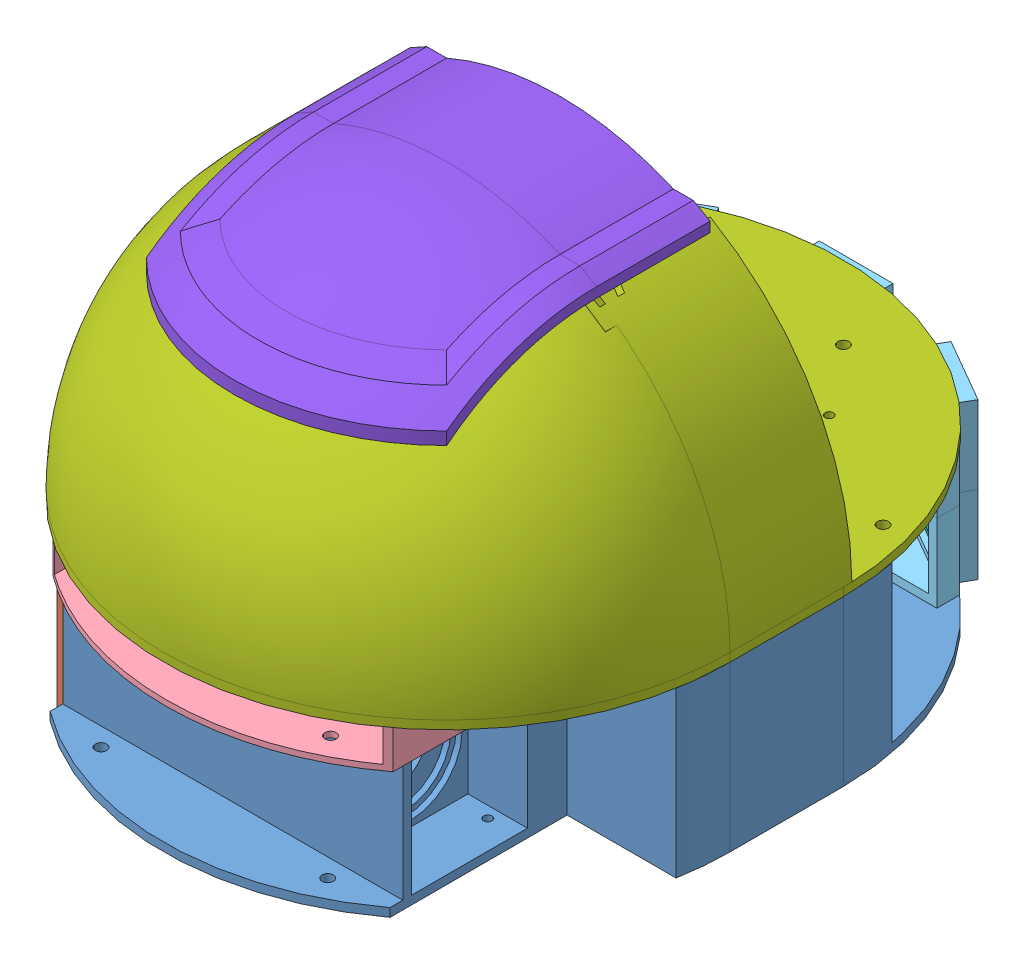
SolidWorks assembly 组装_总装, configuration 默认. Lengths in mm.
Overall size (200 170 244.5).
17 component instances, 10 part files, 6 mates.
Components (placement in the parent):
- 组装_底盘-1: 组装_底盘 [默认] at (-4.5048 5.1483 0) size (200 67 240)
  - 小车底盘Pro-1: 小车底盘Pro [默认] at (12.5491 -35.762 260) size (200 67 240)
  - 电机安装架-1: 电机安装架 [默认] at (-47.4509 -12.262 312) x (0 0 1) z (-1 0 0) size (57 44 24)
  - 电机锁架-1: 电机锁架 [默认] at (-26.4509 8.238 291.5) x (1 0 0) z (0 0 -1) size (25 20.5 41)
  - 电机锁架-5: 电机锁架 [默认] at (51.5491 8.238 332.5) x (-1 0 0) z (0 0 1) size (25 20.5 41)
  - 电机压板-1: 电机压板 [默认] at (12.5491 8.238 259) size (120 14 84.5)
- 组装_车头超声波-1: 组装_车头超声波 [默认] at (11.1815 -12.6087 3.75) size (130 55 36.5)
  - 车头前盖-1: 车头前盖 [默认] at (-3.1373 -12.0049 216.25) size (130 27.5 36.5)
  - 车头前盖-2: 车头前盖 [默认] at (-3.1373 36.9951 216.25) x (-1 0 0) z (0 0 1) size (130 27.5 36.5)
  - 超声波传感器安装板-1: 超声波传感器安装板 [默认] at (-3.1373 12.4951 113.75) x (1 0 0) z (0 -1 0) size (22 7 51)
  - 超声波传感器安装板-2: 超声波传感器安装板 [默认] at (48.1127 12.4951 127.4824) x (0.866025 0 0.5) z (0 -1 0) size (22 7 51)
  - 超声波传感器安装板-3: 超声波传感器安装板 [默认] at (-54.3873 12.4951 127.4824) x (0.866025 0 -0.5) z (0 -1 0) size (22 7 51)
- 组装_安装板-1: 组装_安装板 [默认] at (6.1136 70.9005 0) size (200 103 240)
  - 控制器安装盘-1: 控制器安装盘 [默认] at (1.9306 -43.5142 260) size (200 89.6 240)
  - 弧盖-1: 弧盖 [默认] at (1.9306 -40.5142 260) size (106 33.8 114.95)
  - 控制板托架STM32-1: 控制板托架STM32 [默认] at (1.9306 -13.6674 284.9641) x (1 0 0) z (0 -0.866025 0.5) size (110 4.4 62)
  - 控制板托架树莓派-1: 控制板托架树莓派 [默认] at (1.9306 -9.5142 261) x (-1 0 0) z (0 -1 0) size (110 5 62)
Mates (geometry in assembly coordinates):
- 重合1: coincident: plane of 组装_底盘-1/小车底盘Pro-1 through (8.0443 -27.6136 260) normal (0 1 0); plane of 组装_车头超声波-1/车头前盖-1 through (8.0443 -27.6136 220) normal (0 -1 0)
- 重合2: coincident: plane of 组装_底盘-1/小车底盘Pro-1 through (-10.9557 27.3864 260) normal (-1 0 0); plane of 组装_车头超声波-1/车头前盖-1 through (-10.9557 -27.6136 220) normal (1 0 0)
- 重合3: coincident anti-aligned: plane of 组装_底盘-1/小车底盘Pro-1 through (8.0443 27.3864 137) normal (0 0 -1); plane of 组装_车头超声波-1/车头前盖-2 through (8.0443 27.3864 137) normal (0 0 1)
- 重合4: coincident: plane of 组装_底盘-1/小车底盘Pro-1 through (-91.9557 -27.6136 260) normal (-1 0 0); plane of 组装_安装板-1/控制器安装盘-1 through (-91.9557 30.3864 260) normal (-1 0 0)
- 重合5: coincident: line of 组装_底盘-1/小车底盘Pro-1 through (-91.9557 27.3864 220) axis (0 -1 0); line of 组装_安装板-1/控制器安装盘-1 through (-91.9557 30.3864 220) axis (0 -1 0)
- 重合6: coincident anti-aligned: plane of 组装_底盘-1/小车底盘Pro-1 through (8.0443 27.3864 260) normal (0 1 0); plane of 组装_安装板-1/控制器安装盘-1 through (8.0443 27.3864 260) normal (0 -1 0)
